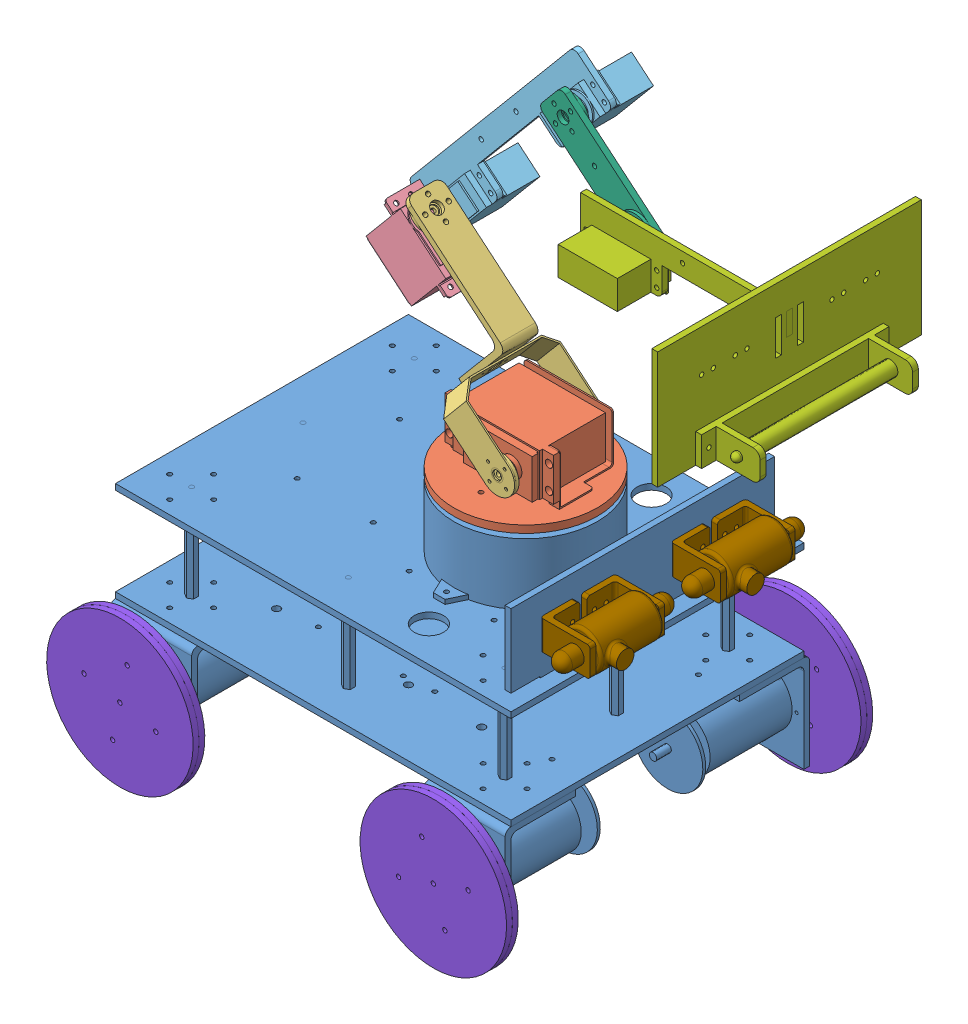
SolidWorks assembly exa_cambase_robot, configuration Default. Lengths in mm.
Overall size (438.25 459.97 250).
13 component instances, 9 part files, 32 mates.
Components (placement in the parent):
- base_cambase_robot-1: base_cambase_robot [Default] at (-6.7047 -18.3672 -0.6285) size (270 185 234)
- link1_robot-1: link1_robot [Default] at (-6.7047 -18.3672 -0.6285) size (98 43 98)
- link2_robot-1: link2_robot [Default] at (-6.7047 -18.3672 -0.6285) size (99.47 123.93 66)
- link3_robot-1: link3_robot [Default] at (-6.7047 -18.3672 -0.6285) size (56.44 54.96 29)
- link4_robot-1: link4_robot [Default] at (-6.7047 -18.3672 -0.6285) size (137.73 155 42.35)
- link5_robot-1: link5_robot [Default] at (-6.7047 -18.3672 -0.6285) size (81.1 72.97 14)
- link6_GM_robot-1: link6_GM_robot [Default] at (-6.7047 -18.3672 -0.6285) size (174.63 80 180)
- roda_robot_fix-1: roda_robot_fix [Default] at (141.5089 78.6443 257.4859) x (0.496857 -0.867833 0) z (0 0 1) size (100 100 21)
- roda_robot_fix-2: roda_robot_fix [Default] at (-31.0252 132.7901 168.5403) x (0.967341 -0.253479 0) z (0 0 -1) size (100 100 21)
- roda_robot_fix-3: roda_robot_fix [Default] at (-47.0283 8.5844 257.4859) size (100 100 21)
- roda_robot_fix-4: roda_robot_fix [Default] at (185.3088 -2.694 168.5403) x (-0.451062 0.892493 0) z (0 0 -1) size (100 100 21)
- webcam_robot-1: webcam_robot [Default] at (-6.7047 -18.3672 -0.6285) size (44 27 79)
- webcam_robot-2: webcam_robot [Default] at (-6.7047 -18.3672 88.3715) size (44 27 79)
Mates (geometry in assembly coordinates):
- Coincident1: coincident anti-aligned: plane of base_cambase_robot-1 through (162.9477 213.6991 222.9191) normal (0 1 0); plane of link1_robot-1 through (152.6607 213.6991 213.0131) normal (0 -1 0)
- Concentric1: concentric aligned: cylinder of base_cambase_robot-1 through (152.6607 194.4435 213.0131) axis (0 1 0) radius 2.8131; cylinder of link1_robot-1 through (152.6607 209.6991 213.0131) axis (0 1 0) radius 3
- Coincident3: coincident anti-aligned: plane of link1_robot-1 through (168.1607 238.6991 245.0031) normal (0 0 1); plane of link2_robot-1 through (168.1607 238.6991 245.0031) normal (0 0 -1)
- Concentric2: concentric anti-aligned: cylinder of link1_robot-1 through (168.1607 238.6991 245.0031) axis (0 0 -1) radius 3; cylinder of link2_robot-1 through (168.1607 238.6991 242.0031) axis (0 0 1) radius 3
- Coincident6: coincident anti-aligned: plane of link2_robot-1 through (89.8837 338.3219 214.5889) normal (-0.642788 -0.766044 0); plane of link3_robot-1 through (89.8837 338.3219 214.5889) normal (0.642788 0.766044 0)
- Concentric3: concentric anti-aligned: cylinder of link2_robot-1 through (87.9553 336.0237 214.5889) axis (0.642788 0.766044 0) radius 3; cylinder of link3_robot-1 through (89.8837 338.3219 214.5889) axis (-0.642788 -0.766044 0) radius 2.9972
- Coincident7: coincident anti-aligned: plane of link3_robot-1 through (78.1876 321.0103 198.6219) normal (0 0 -1); plane of link4_robot-1 through (78.1876 321.0103 198.6219) normal (0 0 1)
- Concentric4: concentric anti-aligned: cylinder of link3_robot-1 through (78.1876 321.0103 195.6219) axis (0 0 1) radius 3; cylinder of link4_robot-1 through (78.1876 321.0103 198.6219) axis (0 0 -1) radius 2.9972
- Coincident8: coincident anti-aligned: plane of link4_robot-1 through (169.8282 429.433 198.6219) normal (0 0 1); plane of link5_robot-1 through (169.8282 429.433 198.6219) normal (0 0 -1)
- Concentric6: concentric anti-aligned: cylinder of link4_robot-1 through (169.8282 429.433 198.6219) axis (0 0 -1) radius 2.9972; cylinder of link5_robot-1 through (169.8282 429.433 195.6219) axis (0 0 1) radius 3
- Coincident9: coincident anti-aligned: plane of link5_robot-1 through (220.3871 387.009 206.6219) normal (0 0 1); plane of link6_GM_robot-1 through (220.3871 387.009 206.6219) normal (0 0 -1)
- Concentric7: concentric anti-aligned: cylinder of link5_robot-1 through (220.3871 387.009 209.6219) axis (0 0 -1) radius 3; cylinder of link6_GM_robot-1 through (220.3871 387.009 206.6219) axis (0 0 1) radius 2.9972
- Coincident12: coincident anti-aligned: plane of base_cambase_robot-1 through (237.5595 21.3617 317.0131) normal (0 0 1); plane of roda_robot_fix-1 through (214.6607 65.5738 317.0131) normal (0 0 -1)
- Concentric9: concentric aligned: cylinder of base_cambase_robot-1 through (214.6607 65.5738 330.0131) axis (0 0 -1) radius 2.5; cylinder of roda_robot_fix-1 through (214.6607 65.5738 330.0131) axis (0 0 -1) radius 2.5
- Coincident13: coincident anti-aligned: plane of base_cambase_robot-1 through (191.7619 21.3617 109.0131) normal (0 0 -1); plane of roda_robot_fix-4 through (214.6607 65.5738 109.0131) normal (0 0 1)
- Concentric10: concentric aligned: cylinder of base_cambase_robot-1 through (214.6607 65.5738 96.0131) axis (0 0 1) radius 2.5; cylinder of roda_robot_fix-4 through (214.6607 65.5738 96.0131) axis (0 0 1) radius 2.5
- Coincident14: coincident anti-aligned: plane of base_cambase_robot-1 through (-22.2381 109.7859 317.0131) normal (0 0 1); plane of roda_robot_fix-3 through (0.6607 65.5738 317.0131) normal (0 0 -1)
- Concentric11: concentric aligned: cylinder of base_cambase_robot-1 through (0.6607 65.5738 330.0131) axis (0 0 -1) radius 2.5; cylinder of roda_robot_fix-3 through (0.6607 65.5738 330.0131) axis (0 0 -1) radius 2.5
- Coincident15: coincident anti-aligned: plane of base_cambase_robot-1 through (-22.2381 21.3617 109.0131) normal (0 0 -1); plane of roda_robot_fix-2 through (0.6607 65.5738 109.0131) normal (0 0 1)
- Concentric12: concentric aligned: cylinder of base_cambase_robot-1 through (0.6607 65.5738 96.0131) axis (0 0 1) radius 2.5; cylinder of roda_robot_fix-2 through (0.6607 65.5738 96.0131) axis (0 0 1) radius 2.5
- Coincident16: coincident anti-aligned: plane of base_cambase_robot-1 through (232.6607 200.6909 215.7137) normal (1 0 0); plane of webcam_robot-2 through (232.6607 204.5738 232.0131) normal (-1 0 0)
- Concentric13: concentric anti-aligned: cylinder of base_cambase_robot-1 through (232.6607 194.5738 273.0131) axis (-1 0 0) radius 1.5; cylinder of webcam_robot-2 through (232.6607 194.5738 273.0131) axis (1 0 0) radius 1.5
- Concentric14: concentric anti-aligned: cylinder of base_cambase_robot-1 through (232.6607 194.5738 242.0131) axis (-1 0 0) radius 1.5; cylinder of webcam_robot-2 through (232.6607 194.5738 242.0131) axis (1 0 0) radius 1.5
- Coincident18: coincident anti-aligned: plane of base_cambase_robot-1 through (232.6607 200.6909 215.7137) normal (1 0 0); plane of webcam_robot-1 through (232.6607 184.5738 194.0131) normal (-1 0 0)
- Concentric15: concentric anti-aligned: cylinder of base_cambase_robot-1 through (232.6607 194.5738 184.0131) axis (-1 0 0) radius 1.5; cylinder of webcam_robot-1 through (232.6607 194.5738 184.0131) axis (1 0 0) radius 1.5
- Concentric16: concentric anti-aligned: cylinder of base_cambase_robot-1 through (232.6607 194.5738 153.0131) axis (-1 0 0) radius 1.5; cylinder of webcam_robot-1 through (232.6607 194.5738 153.0131) axis (1 0 0) radius 1.5
- LimitAngle1: limit planar angle = 1.570796 rad anti-aligned: plane of link1_robot-1 through (162.7616 193.5691 238.0031) normal (0 0 1); plane of base_cambase_robot-1 through (242.6607 164.5738 196.8798) normal (1 0 0)
- LimitAngle2: limit planar angle = 2.443461 rad aligned: plane of link1_robot-1 through (152.6607 218.6991 213.0131) normal (0 1 0); plane of link2_robot-1 through (130.5856 254.5634 201.7097) normal (-0.642788 -0.766044 0)
- LimitAngle3: limit planar angle = 1.570796 rad anti-aligned: plane of link3_robot-1 through (72.6686 332.624 224.6219) normal (-0.766044 0.642788 0); plane of link2_robot-1 through (88.545 295.1295 226.5889) normal (0 0 1)
- LimitAngle4: limit planar angle = 0 rad anti-aligned: plane of link4_robot-1 through (186.4508 488.8751 188.8424) normal (-0.766044 0.642788 0); plane of link3_robot-1 through (103.606 306.6644 224.6219) normal (0.766044 -0.642788 0)
- LimitAngle5: limit planar angle = 0 rad aligned: plane of link5_robot-1 through (168.3491 446.3389 204.6219) normal (0.642788 0.766044 0); plane of link4_robot-1 through (168.265 443.1786 183.1914) normal (0.642788 0.766044 0)
- LimitAngle6: limit planar angle = 2.268928 rad anti-aligned: plane of link5_robot-1 through (168.3491 446.3389 204.6219) normal (0.642788 0.766044 0); plane of link6_GM_robot-1 through (251.2481 397.042 222.0524) normal (1 0 0)
